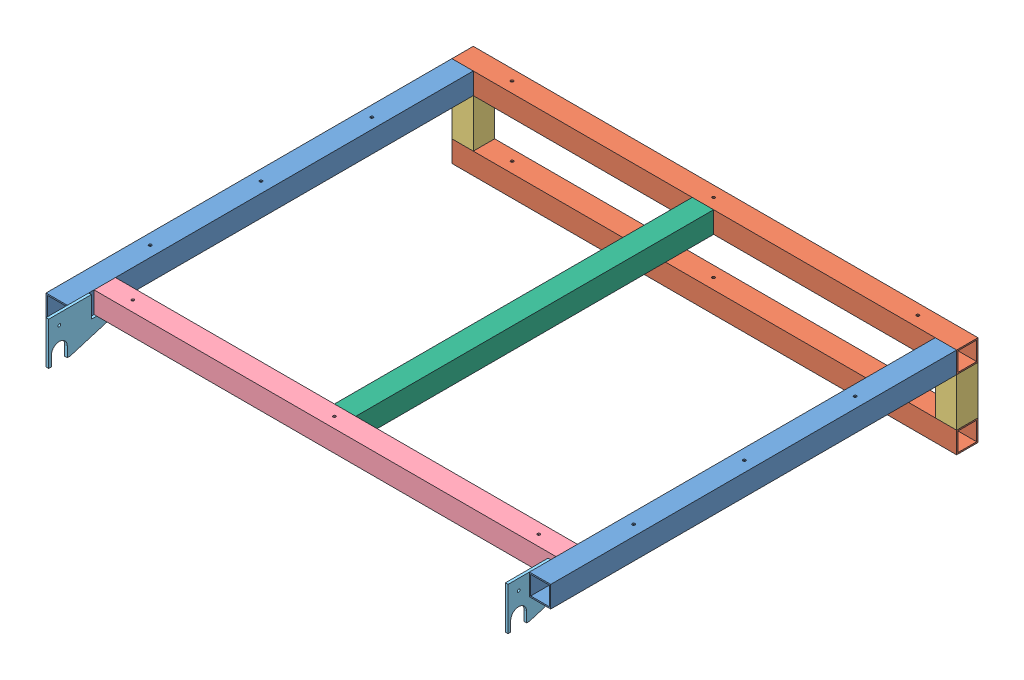
SolidWorks assembly GE-19032, configuration Default. Lengths in mm.
Overall size (1200.15 215.9 1066.8).
10 component instances, 6 part files, 29 mates.
Components (placement in the parent):
- GE-19032-01-2: GE-19032-01 [Default] at (1832.274 165.1 50.8) size (50.8 50.8 965.2)
- GE-19032-01-3: GE-19032-01 [Default] at (682.924 165.1 50.8) size (50.8 50.8 965.2)
- GE-19032-02-3: GE-19032-02 [Default] at (1857.674 190.5 25.4) x (0 1 0) z (0 0 1) size (50.8 1200.15 50.8)
- GE-19032-03-3: GE-19032-03 [Default] at (1832.274 50.8 25.4) size (50.8 114.3 50.8)
- GE-19032-03-4: GE-19032-03 [Default] at (682.924 50.8 25.4) size (50.8 114.3 50.8)
- GE-19032-02-4: GE-19032-02 [Default] at (1857.674 25.4 25.4) x (0 1 0) z (0 0 1) size (50.8 1200.15 50.8)
- GE-19032-04-1: GE-19032-04 [Default] at (1806.874 165.1 -1412.431) x (0 0 1) z (-1 0 0) size (50.8 50.8 1098.55)
- GE-19032-05-5: GE-19032-05 [Default] at (714.674 165.1 50.8002) x (0 0 1) z (-1 0 0) size (177.8 101.6 6.35)
- GE-19032-05-6: GE-19032-05 [Default] at (1806.874 165.1 50.8) x (0 0 1) z (-1 0 0) size (177.8 101.6 6.35)
- GE-19032-06-1: GE-19032-06 [Default] at (1254.424 190.5 50.8) x (1 0 0) z (0 -1 0) size (50.8 850.9 50.8)
Mates (geometry in assembly coordinates):
- Coincident24: coincident: plane of assembly; plane of assembly; plane of GE-19032-03-4 through (682.924 50.8 25.4) normal (0 -1 0); plane of GE-19032-02-4 through (657.524 50.8 50.8) normal (0 1 0)
- Coincident25: coincident: plane of assembly; plane of assembly; plane of GE-19032-02-3 through (657.524 215.9 50.8) normal (0 0 1); plane of GE-19032-03-3 through (1857.674 165.1 50.8) normal (0 0 1)
- Coincident26: coincident: plane of assembly; plane of assembly; plane of GE-19032-02-3 through (1857.674 190.5 25.4) normal (1 0 0); plane of GE-19032-03-3 through (1857.674 165.1 50.8) normal (1 0 0)
- Coincident27: coincident: plane of assembly; plane of assembly; plane of GE-19032-03-3 through (1832.274 50.8 25.4) normal (0 -1 0); plane of GE-19032-02-4 through (657.524 50.8 50.8) normal (0 1 0)
- Coincident28: coincident: plane of assembly; plane of assembly; plane of GE-19032-03-3 through (1857.674 165.1 50.8) normal (0 0 1); plane of GE-19032-02-4 through (657.524 50.8 50.8) normal (0 0 1)
- Coincident29: coincident: plane of assembly; plane of assembly; plane of GE-19032-02-3 through (657.524 165.1 50.8) normal (0 -1 0); plane of GE-19032-03-3 through (1832.274 165.1 25.4) normal (0 1 0)
- Coincident30: coincident: plane of assembly; plane of assembly; plane of GE-19032-03-4 through (708.324 165.1 50.8) normal (0 0 1); plane of GE-19032-02-4 through (657.524 50.8 50.8) normal (0 0 1)
- Coincident31: coincident: plane of assembly; plane of assembly; plane of GE-19032-03-3 through (1857.674 165.1 50.8) normal (1 0 0); plane of GE-19032-02-4 through (1857.674 25.4 25.4) normal (1 0 0)
- Coincident32: coincident: plane of assembly; plane of assembly; plane of GE-19032-03-4 through (657.524 165.1 50.8) normal (-1 0 0); plane of GE-19032-02-4 through (657.524 25.4 25.4) normal (-1 0 0)
- Coincident33: coincident: plane of GE-19032-01-2 through (1832.274 165.1 50.8) normal (0 0 -1); plane of GE-19032-02-3 through (657.524 215.9 50.8) normal (0 0 1)
- Coincident34: coincident: plane of GE-19032-01-2 through (1806.874 215.9 1016) normal (0 1 0); plane of GE-19032-02-3 through (657.524 215.9 50.8) normal (0 1 0)
- Coincident35: coincident: plane of GE-19032-01-2 through (1857.674 165.1 1016) normal (1 0 0); plane of GE-19032-02-3 through (1857.674 190.5 25.4) normal (1 0 0)
- Coincident36: coincident: plane of assembly; plane of assembly; plane of GE-19032-01-3 through (682.924 165.1 50.8) normal (0 0 -1); plane of GE-19032-02-3 through (657.524 215.9 50.8) normal (0 0 1)
- Coincident37: coincident: plane of assembly; plane of assembly; plane of GE-19032-01-3 through (657.524 165.1 1016) normal (-1 0 0); plane of GE-19032-02-3 through (657.524 190.5 25.4) normal (-1 0 0)
- Coincident38: coincident: plane of assembly; plane of assembly; plane of GE-19032-01-3 through (657.524 215.9 1016) normal (0 1 0); plane of GE-19032-02-3 through (657.524 215.9 50.8) normal (0 1 0)
- Coincident39: coincident: plane of assembly through (0 0 0) normal (0 1 0); plane of GE-19032-02-4 through (657.524 0 50.8) normal (0 -1 0); plane of assembly
- Coincident40: coincident: plane of assembly through (0 0 0) normal (0 0 1); plane of GE-19032-02-3 through (657.524 215.9 0) normal (0 0 -1); plane of assembly
- Coincident104: coincident: point of GE-19032-01-2; moEndPointRef_w of GE-19032-05-6
- Coincident105: coincident: plane of GE-19032-01-2 through (1806.874 165.1 1016) normal (-1 0 0); plane of GE-19032-05-6 through (1806.874 165.1 50.8) normal (1 0 0)
- Distance2: distance = 50.8 mm: plane of GE-19032-05-6 through (1800.524 165.1 965.2) normal (0 0 -1); plane of GE-19032-01-2 through (1832.274 165.1 1016) normal (0 0 1)
- Coincident114: coincident: plane of assembly; plane of assembly; plane of GE-19032-01-3 through (657.524 215.9 1016) normal (0 1 0); plane of GE-19032-05-5 through (708.324 215.9 50.8002) normal (0 1 0)
- Coincident115: coincident: plane of assembly; plane of assembly; plane of GE-19032-01-3 through (708.324 165.1 1016) normal (1 0 0); plane of GE-19032-05-5 through (708.324 165.1 50.8002) normal (-1 0 0)
- Coincident139: coincident: plane of assembly; plane of assembly; plane of GE-19032-02-3 through (657.524 215.9 50.8) normal (0 0 1); plane of GE-19032-06-1 through (1254.424 190.5 50.8) normal (0 0 -1)
- Distance14: distance = 527.05 mm: plane of GE-19032-01-2 through (1806.874 165.1 1016) normal (-1 0 0); plane of GE-19032-06-1 through (1279.824 165.1 973.5422) normal (1 0 0)
- Coincident143: coincident: plane of assembly; plane of assembly; plane of GE-19032-02-3 through (657.524 165.1 50.8) normal (0 -1 0); plane of GE-19032-06-1 through (1279.824 165.1 973.5422) normal (0 -1 0)
- Distance16: distance = 12.7 mm: plane of assembly; plane of assembly; plane of GE-19032-04-1 through (708.324 165.1 901.7002) normal (0 0 -1); plane of GE-19032-05-5 through (708.324 165.1 889.0002) normal (0 0 -1)
- Coincident146: coincident: plane of assembly; plane of assembly; plane of GE-19032-01-3 through (708.324 165.1 1016) normal (1 0 0); plane of GE-19032-04-1 through (708.324 165.1 -1412.431) normal (-1 0 0)
- Coincident147: coincident: plane of assembly; plane of assembly; plane of GE-19032-04-1 through (708.324 165.1 901.7002) normal (0 0 -1); plane of GE-19032-06-1 through (708.324 165.1 901.7002) normal (0 0 1)
- Coincident148: coincident: plane of GE-19032-01-2 through (1806.874 215.9 1016) normal (0 1 0); plane of GE-19032-04-1 through (708.324 215.9 901.7002) normal (0 1 0)
